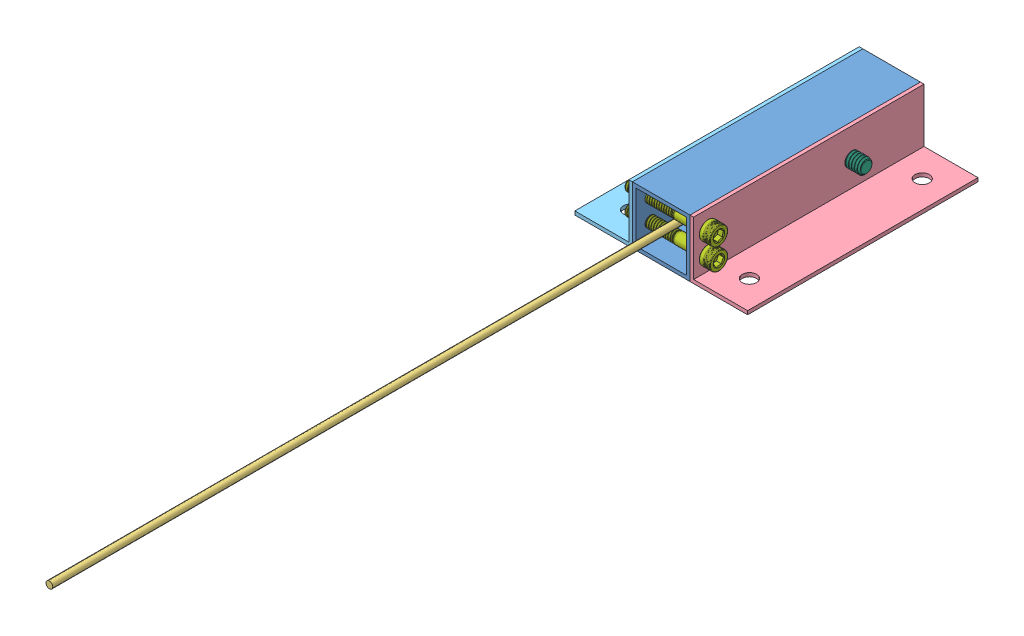
SolidWorks assembly ArrayLockV4, configuration Default. Lengths in mm.
Overall size (76.2 25.4 371.41).
9 component instances, 8 part files, 17 mates.
Components (placement in the parent):
- aluminumsquarestock-1: aluminumsquarestock [Default] at origin size (25.4 25.4 101.6)
- Delrin-1: Delrin [Default] at (-11.1125 -11.1125 79.375) x (0 0 -1) z (1 0 0) size (73.03 22.23 22.23)
- fake string-1: fake string [Default] at (0 0 79.375) x (0 0 1) z (-0.809147 -0.587606 0) size (292.03 9.53 9.53)
- Part1^ArrayLockV4-1: Part1^ArrayLockV4 [Default] at origin (virtual)
- anglebracket-1: anglebracket [Default] at (12.7 -12.7 101.6) x (0 0 -1) z (1 0 0) size (101.6 25.4 25.4)
- anglebracket - Mirror-1: anglebracket - Mirror [Default] at (-12.7 -12.7 101.6) x (0 0 -1) z (1 0 0) size (101.6 25.4 25.4)
- 91251A543_Black-Oxide Alloy Steel Socket Head Screw-1: 91251A543_Black-Oxide Alloy Steel Socket Head Screw [91251A543] at (0 0 31.75) x (0 0.806909 0.590676) z (-1 0 0) size (9.53 9.53 42.05)
- 91251A250_Black-Oxide Alloy Steel Socket Head Screw-1: 91251A250_Black-Oxide Alloy Steel Socket Head Screw [91251A250] at (-0.762 -4.7625 95.25) x (0 -0.997127 -0.075745) z (1 0 0) size (7.94 7.94 40.24)
- 91251A250_Black-Oxide Alloy Steel Socket Head Screw-3: 91251A250_Black-Oxide Alloy Steel Socket Head Screw [91251A250] at (-0.762 4.7625 95.25) x (0 0.152164 0.988355) z (1 0 0) size (7.94 7.94 40.24)
Mates (geometry in assembly coordinates):
- Coincident1: coincident anti-aligned: plane of aluminumsquarestock-1 through (-11.1125 -11.1125 101.6) normal (1 0 0); plane of Delrin-1 through (-11.1125 -11.1125 79.375) normal (-1 0 0)
- Coincident2: coincident anti-aligned: plane of aluminumsquarestock-1 through (-11.1125 -11.1125 101.6) normal (0 1 0); plane of Delrin-1 through (11.1125 -11.1125 6.35) normal (0 -1 0)
- Coincident5: coincident anti-aligned: plane of Delrin-1 through (11.1125 -11.1125 79.375) normal (0 0 1); plane of fake string-1 through (0 0 79.375) normal (0 0 -1)
- LimitDistance1: limit distance = 25.4 mm aligned: plane of aluminumsquarestock-1 through (0 0 0) normal (0 0 -1); plane of Delrin-1 through (11.1125 11.1125 25.4) normal (0 0 -1)
- Parallel2: parallel aligned: cylinder of Delrin-1 through (7.9375 0 6.349) axis (0 0 1) radius 3.175; cylinder of fake string-1 through (0 0 371.4057) axis (0 0 1) radius 1.5
- Coincident6: coincident anti-aligned: circle of aluminumsquarestock-1; circle of anglebracket - Mirror-1
- Coincident7: coincident anti-aligned: circle of aluminumsquarestock-1; circle of anglebracket - Mirror-1
- Coincident8: coincident aligned: circle of aluminumsquarestock-1; circle of anglebracket-1
- Coincident9: coincident aligned: circle of aluminumsquarestock-1; circle of anglebracket-1
- Concentric21: concentric aligned: cylinder of anglebracket - Mirror-1 through (-112.7125 0 31.75) axis (1 0 0) radius 3.175; cone of 91251A543_Black-Oxide Alloy Steel Socket Head Screw-1 through (-14.2875 0 31.75) axis (1 0 0)
- Coincident101: coincident anti-aligned: plane of anglebracket - Mirror-1 through (-14.2875 12.7 0) normal (-1 0 0); plane of 91251A543_Black-Oxide Alloy Steel Socket Head Screw-1 through (-14.2875 -3.5867 29.1244) normal (1 0 0)
- Concentric3: concentric anti-aligned: cylinder of anglebracket-1 through (-87.3125 -4.7625 95.25) axis (1 0 0) radius 2.3813; cylinder of 91251A250_Black-Oxide Alloy Steel Socket Head Screw-1 through (21.2562 -4.7625 95.25) axis (-1 0 0) radius 2.4638
- Coincident11: coincident anti-aligned: plane of anglebracket-1 through (14.2875 12.7 0) normal (1 0 0); plane of 91251A250_Black-Oxide Alloy Steel Socket Head Screw-1 through (14.2875 -4.5797 92.8439) normal (-1 0 0)
- Concentric51: concentric anti-aligned: cylinder of anglebracket-1 through (-87.3125 4.7625 95.25) axis (1 0 0) radius 2.3813; cone of 91251A250_Black-Oxide Alloy Steel Socket Head Screw-3 through (19.1135 4.7625 95.25) axis (-1 0 0)
- Coincident14: coincident anti-aligned: plane of anglebracket-1 through (14.2875 12.7 0) normal (1 0 0); plane of 91251A250_Black-Oxide Alloy Steel Socket Head Screw-3 through (14.2875 2.3776 95.6172) normal (-1 0 0)
- Distance1: distance = 11.1125 mm: plane of Delrin-1 through (11.1125 11.1125 79.375) normal (0 1 0); cylinder of fake string-1 through (0 0 371.4057) axis (0 0 1) radius 1.5
- Distance2: distance = 11.1125 mm: plane of Delrin-1 through (11.1125 -11.1125 79.375) normal (1 0 0); cylinder of fake string-1 through (0 0 371.4057) axis (0 0 1) radius 1.5
